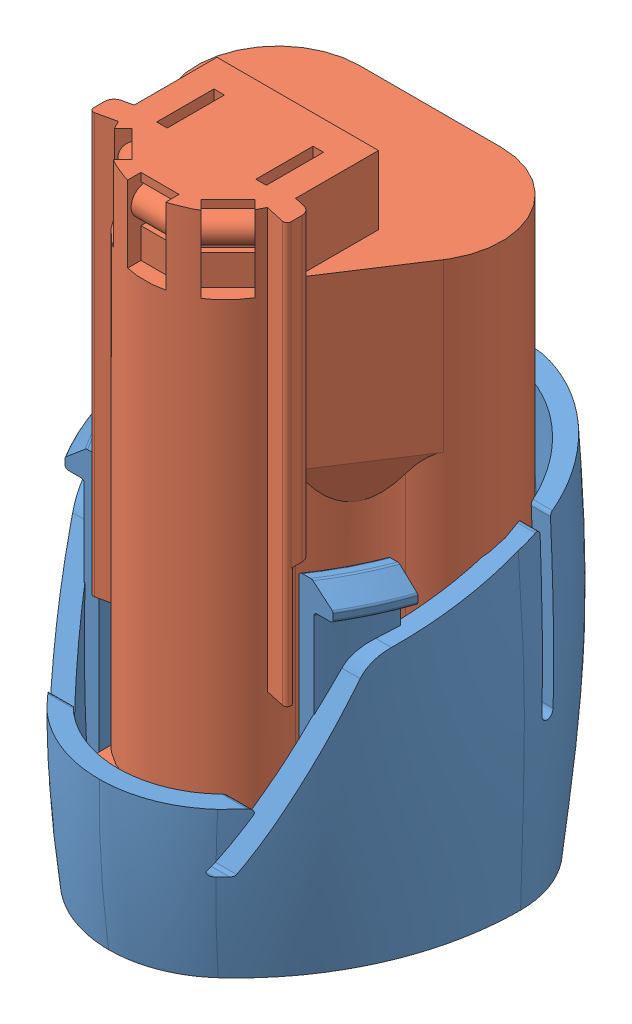
SolidWorks assembly Milwaukee M12 Drill Battery, configuration Default. Lengths in mm.
Overall size (49.98 85.02 54.25).
2 component instances, 2 part files, 3 mates.
Components (placement in the parent):
- Milwaukee M12 drill battery - case-1: Milwaukee M12 drill battery - case [Default] at origin size (49.98 47.94 54.25)
- Milwaukee M12 drill battery - 8-30-18 v1-1: Milwaukee M12 drill battery - 8-30-18 v1 [Default] at (0 0.3048 0) size (40.63 82.52 39.88)
Mates (geometry in assembly coordinates):
- Coincident1: coincident anti-aligned: plane of Milwaukee M12 drill battery - case-1 through (7.454 0.3048 2.7305) normal (0 1 0); plane of Milwaukee M12 drill battery - 8-30-18 v1-1 through (4.7294 0.3048 -17.0763) normal (0 -1 0)
- Coincident2: coincident aligned: plane of Milwaukee M12 drill battery - 8-30-18 v1-1 through (0 0.3048 0) normal (0 0 1)
- Coincident3: coincident aligned: plane of Milwaukee M12 drill battery - 8-30-18 v1-1 through (0 0.3048 0) normal (1 0 0)
